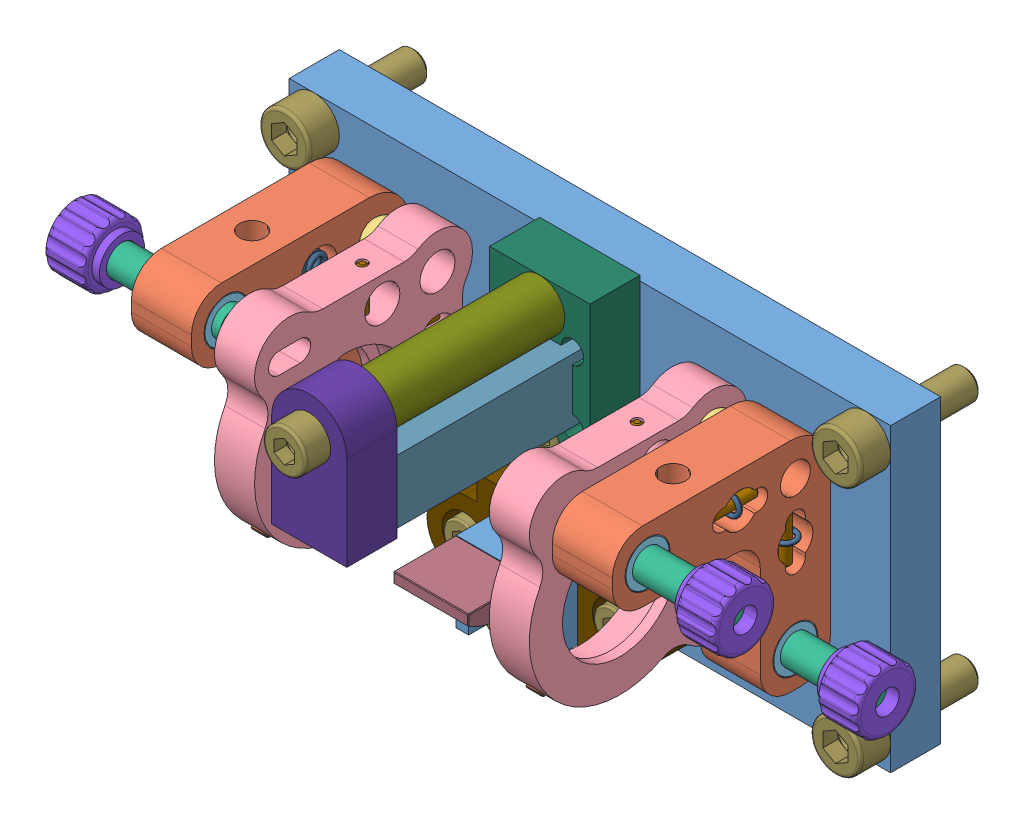
SolidWorks assembly Dye Laser, configuration Standard. Lengths in mm.
Overall size (135.01 63.5 81).
57 component instances, 19 part files, 47 mates.
Components (placement in the parent):
- Base plate-1: Base plate [Standard] at origin size (120 60 10)
- AssemblyEO-1: AssemblyEO [Standard] at (42 -20.7016 6.8571) x (0 -1 0) z (-1 0 0) size (43.98 43.98 44.09)
  - Base-1: Base [Standard] at (-20.7016 28.5429 -6) size (43.5 43.5 12)
  - Ball Bearing 8mm-1: Ball Bearing 8mm [Standard] at (-39.1016 10.1429 8.6458) x (0 0 1) z (-0.991419 0.130726 0) size (8 8 8)
  - Mount-1: Mount [Standard] at (-20.7016 28.5429 10.5822) size (43.5 43.5 8)
  - BushingM6-1: BushingM6 [Standard] at (-39.1016 39.6429 -6) size (9 9 12)
  - BushingM6-2: BushingM6 [Standard] at (-9.6016 10.1429 -6) x (-0.892855 0.450344 0) z (0 0 1) size (9 9 12)
  - Adjustment screw-1: Adjustment screw [Standard] at (-9.6016 10.1429 8.1361) x (0 0 -1) z (0.374671 -0.927158 0) size (30 6 6)
  - Adjustment screw-2: Adjustment screw [Standard] at (-39.1016 39.6429 6.9925) x (0 0 -1) z (-0.963766 0.266748 0) size (30 6 6)
  - BallBearing5mm-1: BallBearing5mm [Standard] at (-9.6016 10.1429 9.2258) x (0.281645 -0.210353 0.936177) z (-0.880072 -0.445363 0.164696) size (5 5 5)
  - BallBearing5mm-2: BallBearing5mm [Standard] at (-39.1016 39.6429 8.0822) x (0.754667 -0.477905 0.449538) z (-0.133948 -0.782951 -0.607491) size (5 5 5)
  - Screw handle-1: Screw handle [Standard] at (-35.834 68.9613 -4.0071) x (0.993846 -0.110766 0) z (0 0 -1) size (13.55 13.55 9.5)
  - Screw handle-2: Screw handle [Standard] at (19.8922 9.5359 -2.8635) x (-0.020573 -0.999788 0) z (0 0 -1) size (13.55 13.55 9.5)
  - 2mm pin-1: 2mm pin [Standard] at (-44.1016 21.1429 14.5822) x (0 0 -1) z (1 0 0) size (2 2 10)
  - 2mm pin-2: 2mm pin [Standard] at (-28.1016 15.1429 14.5822) x (0 0 -1) z (0 -1 0) size (2 2 10)
  - 2mm pin-3: 2mm pin [Standard] at (-33.1016 10.1429 -4) x (0 0 1) z (1 0 0) size (2 2 10)
  - 2mm pin-4: 2mm pin [Standard] at (-39.1016 26.1429 -4) x (0 0 1) z (0 -1 0) size (2 2 10)
  - Gutekunst RZ_081QX_1.stp-1: Gutekunst RZ_081QX_1.stp [Standard] at (-39.1016 21.1429 -2.64) size (4.57 4.57 15.99)
  - Gutekunst RZ_081QX_1.stp-2: Gutekunst RZ_081QX_1.stp [Standard] at (-28.1016 10.1429 -2.64) x (0 -1 0) z (0 0 1) size (4.57 4.57 15.99)
  - socket set screw dog point_din-2: socket set screw dog point_din [DIN 915 - M3 x 5-N] at (-7.6201 41.6243 14.5822) x (-0.707107 -0.707107 0) z (0 0 1) size (5 3 3)
- AssemblyEO-2: AssemblyEO [Standard] at (-42 28.5429 56.1016) x (0 0 1) z (1 0 0) size (43.98 43.98 44.09)
  - Base-1: Base [Standard] at (-20.7016 28.5429 -6) size (43.5 43.5 12)
  - Ball Bearing 8mm-1: Ball Bearing 8mm [Standard] at (-39.1016 10.1429 8.6458) x (0 0 1) z (-0.991419 0.130726 0) size (8 8 8)
  - Mount-1: Mount [Standard] at (-20.7016 28.5429 10.5822) size (43.5 43.5 8)
  - BushingM6-1: BushingM6 [Standard] at (-39.1016 39.6429 -6) size (9 9 12)
  - BushingM6-2: BushingM6 [Standard] at (-9.6016 10.1429 -6) x (-0.892855 0.450344 0) z (0 0 1) size (9 9 12)
  - Adjustment screw-1: Adjustment screw [Standard] at (-9.6016 10.1429 8.1361) x (0 0 -1) z (0.374671 -0.927158 0) size (30 6 6)
  - Adjustment screw-2: Adjustment screw [Standard] at (-39.1016 39.6429 6.9925) x (0 0 -1) z (-0.963766 0.266748 0) size (30 6 6)
  - BallBearing5mm-1: BallBearing5mm [Standard] at (-9.6016 10.1429 9.2258) x (0.281645 -0.210353 0.936177) z (-0.880072 -0.445363 0.164696) size (5 5 5)
  - BallBearing5mm-2: BallBearing5mm [Standard] at (-39.1016 39.6429 8.0822) x (0.754667 -0.477905 0.449538) z (-0.133948 -0.782951 -0.607491) size (5 5 5)
  - Screw handle-1: Screw handle [Standard] at (-35.834 68.9613 -4.0071) x (0.993846 -0.110766 0) z (0 0 -1) size (13.55 13.55 9.5)
  - Screw handle-2: Screw handle [Standard] at (19.8922 9.5359 -2.8635) x (-0.020573 -0.999788 0) z (0 0 -1) size (13.55 13.55 9.5)
  - 2mm pin-1: 2mm pin [Standard] at (-44.1016 21.1429 14.5822) x (0 0 -1) z (1 0 0) size (2 2 10)
  - 2mm pin-2: 2mm pin [Standard] at (-28.1016 15.1429 14.5822) x (0 0 -1) z (0 -1 0) size (2 2 10)
  - 2mm pin-3: 2mm pin [Standard] at (-33.1016 10.1429 -4) x (0 0 1) z (1 0 0) size (2 2 10)
  - 2mm pin-4: 2mm pin [Standard] at (-39.1016 26.1429 -4) x (0 0 1) z (0 -1 0) size (2 2 10)
  - Gutekunst RZ_081QX_1.stp-1: Gutekunst RZ_081QX_1.stp [Standard] at (-39.1016 21.1429 -2.64) size (4.57 4.57 15.99)
  - Gutekunst RZ_081QX_1.stp-2: Gutekunst RZ_081QX_1.stp [Standard] at (-28.1016 10.1429 -2.64) x (0 -1 0) z (0 0 1) size (4.57 4.57 15.99)
  - socket set screw dog point_din-2: socket set screw dog point_din [DIN 915 - M3 x 5-N] at (-7.6201 41.6243 14.5822) x (-0.707107 -0.707107 0) z (0 0 1) size (5 3 3)
- socket head cap screw_din-1: socket head cap screw_din [DIN 912 M4 x 20 --- 20N] at (-42 0 23.6) x (0 0 -1) z (1 0 0) size (24 7 7)
- socket head cap screw_din-2: socket head cap screw_din [DIN 912 M4 x 20 --- 20N] at (42 0 23.6) x (0 0 -1) z (1 0 0) size (24 7 7)
- LJ1638L1-A-Solidworks-1: LJ1638L1-A-Solidworks [Default] at (-0.1002 -15.065 35.4) x (1 0 0) z (0 -1 0) size (15 12.5 3.85)
- Cuvet-1: Cuvet [Standard] at (0.2 14.3 10) size (12.6 12.6 45)
- socket head cap screw_din-3: socket head cap screw_din [DIN 912 M6 x 20 --- 20N] at (-55 -25 16) x (0 0 -1) z (1 0 0) size (26 10 10)
- socket head cap screw_din-4: socket head cap screw_din [DIN 912 M6 x 20 --- 20N] at (55 -25 16) x (0 0 -1) z (1 0 0) size (26 10 10)
- socket head cap screw_din-5: socket head cap screw_din [DIN 912 M6 x 20 --- 20N] at (55 25 16) x (0 0 -1) z (1 0 0) size (26 10 10)
- socket head cap screw_din-6: socket head cap screw_din [DIN 912 M6 x 20 --- 20N] at (-55 25 16) x (0 0 -1) z (1 0 0) size (26 10 10)
- CuvetHolderBase-1: CuvetHolderBase [Standard] at (0 14.5 10) x (0 1 0) z (0 0 1) size (33 20 10)
- socket head cap screw_din-8: socket head cap screw_din [DIN 912 M4 x 16 --- 16N] at (0 3 19.6) x (0 0 -1) z (1 0 0) size (20 7 7)
- CuvetHolderArm-1: CuvetHolderArm [Standard] at (0 26 56) x (0 0 -1) z (-1 0 0) size (44 10 10)
- CuvetHolderClamp-1: CuvetHolderClamp [Standard] at (0 26 56) x (0 1 0) z (0 0 1) size (26.25 15 10)
- socket head cap screw_din-9: socket head cap screw_din [DIN 912 M5 x 16 --- 16N] at (0 26 71) x (0 0 -1) z (1 0 0) size (21 8.5 8.5)
- Rail-1: Rail [Standard] at (22.5 -29.5 10) x (0 1 0) z (0 0 1) size (20 45 10)
- socket head cap screw_din-11: socket head cap screw_din [DIN 912 M4 x 16 --- 16N] at (15 -22 20.9) x (0 0 -1) z (1 0 0) size (20 7 7)
- socket head cap screw_din-12: socket head cap screw_din [DIN 912 M4 x 16 --- 16N] at (-15 -22 20.9) x (0 0 -1) z (1 0 0) size (20 7 7)
- Lensholder-1: Lensholder [Standard] at (7.45 -29.14 19.15) x (0 1 0) z (0 0 1) size (16 15 10)
- socket head cap screw_din-13: socket head cap screw_din [DIN 912 M4 x 10 --- 10N] at (0 -24.5 28.15) x (0 0 -1) z (-0.630869 -0.775889 0) size (14 7 7)
Mates (geometry in assembly coordinates):
- Deckungsgleich1: coincident anti-aligned: plane of Base plate-1 through (0 0 10) normal (0 0 1); plane of AssemblyEO-2/Base-1 through (-36 -18.1 10) normal (0 0 -1)
- Deckungsgleich2: coincident anti-aligned: plane of Base plate-1 through (0 0 10) normal (0 0 1); plane of AssemblyEO-1/Base-1 through (36 17.4 10) normal (0 0 -1)
- Konzentrisch1: concentric aligned: cylinder of Base plate-1 through (-42 0 10) axis (0 0 1) radius 2.1; cylinder of AssemblyEO-2/Base-1 through (-42 0 24) axis (0 0 1) radius 2.5
- Konzentrisch2: concentric aligned: cylinder of Base plate-1 through (42 0 10) axis (0 0 1) radius 2.1; cylinder of AssemblyEO-1/Base-1 through (42 0 24) axis (0 0 1) radius 2.5
- Parallel1: parallel aligned: plane of Base plate-1 through (60 30 10) normal (1 0 0); plane of AssemblyEO-1/Base-1 through (48 6.4 29) normal (1 0 0)
- Parallel2: parallel aligned: plane of Base plate-1 through (-60 30 10) normal (-1 0 0); plane of AssemblyEO-2/Base-1 through (-48 6.4 29) normal (-1 0 0)
- Konzentrisch3: concentric aligned: cylinder of AssemblyEO-2/Base-1 through (-42 0 24) axis (0 0 1) radius 2.5; cylinder of socket head cap screw_din-1 through (-42 0 55.35) axis (0 0 1) radius 3.5
- Deckungsgleich3: coincident anti-aligned: plane of AssemblyEO-2/Base-1 through (-42 -2.5 19.6) normal (0 0 1); plane of socket head cap screw_din-1 through (-42 3.5 19.6) normal (0 0 -1)
- Konzentrisch4: concentric aligned: cylinder of AssemblyEO-1/Base-1 through (42 0 24) axis (0 0 1) radius 2.5; cylinder of socket head cap screw_din-2 through (42 0 55.35) axis (0 0 1) radius 3.5
- Deckungsgleich4: coincident anti-aligned: plane of AssemblyEO-1/Base-1 through (42 -2.5 19.6) normal (0 0 1); plane of socket head cap screw_din-2 through (42 3.5 19.6) normal (0 0 -1)
- Deckungsgleich5: coincident anti-aligned: plane of Base plate-1 through (0 0 10) normal (0 0 1); plane of Cuvet-1 through (0.2 14.3 10) normal (0 0 -1)
- Konzentrisch5: concentric aligned: cylinder of Base plate-1 through (-55 -25 10) axis (0 0 1) radius 2.5; cylinder of socket head cap screw_din-3 through (-55 -25 47.75) axis (0 0 1) radius 5
- Deckungsgleich6: coincident anti-aligned: plane of Base plate-1 through (0 0 10) normal (0 0 1); plane of socket head cap screw_din-3 through (-55 -20 10) normal (0 0 -1)
- Konzentrisch6: concentric aligned: cylinder of Base plate-1 through (55 -25 10) axis (0 0 1) radius 2.5; cylinder of socket head cap screw_din-4 through (55 -25 47.75) axis (0 0 1) radius 5
- Deckungsgleich7: coincident anti-aligned: plane of Base plate-1 through (0 0 10) normal (0 0 1); plane of socket head cap screw_din-4 through (55 -20 10) normal (0 0 -1)
- Konzentrisch7: concentric aligned: cylinder of Base plate-1 through (55 25 10) axis (0 0 1) radius 2.5; cylinder of socket head cap screw_din-5 through (55 25 47.75) axis (0 0 1) radius 5
- Deckungsgleich8: coincident anti-aligned: plane of Base plate-1 through (0 0 10) normal (0 0 1); plane of socket head cap screw_din-5 through (55 30 10) normal (0 0 -1)
- Konzentrisch8: concentric aligned: cylinder of Base plate-1 through (-55 25 10) axis (0 0 1) radius 2.5; cylinder of socket head cap screw_din-6 through (-55 25 47.75) axis (0 0 1) radius 5
- Deckungsgleich9: coincident anti-aligned: plane of Base plate-1 through (0 0 10) normal (0 0 1); plane of socket head cap screw_din-6 through (-55 30 10) normal (0 0 -1)
- Konzentrisch9: concentric aligned: cylinder of Base plate-1 through (0 3 10) axis (0 0 1) radius 1.65; cylinder of CuvetHolderBase-1 through (0 3 20) axis (0 0 1) radius 2.25
- Konzentrisch11: concentric aligned: cylinder of CuvetHolderBase-1 through (0 3 20) axis (0 0 1) radius 2.25; cylinder of socket head cap screw_din-8 through (0 3 51.35) axis (0 0 1) radius 3.5
- Deckungsgleich11: coincident anti-aligned: plane of CuvetHolderBase-1 through (0 5.25 15.6) normal (0 0 1); plane of socket head cap screw_din-8 through (0 6.5 15.6) normal (0 0 -1)
- Deckungsgleich12: coincident anti-aligned: plane of Base plate-1 through (0 0 10) normal (0 0 1); plane of CuvetHolderBase-1 through (0 14.5 10) normal (0 0 -1)
- Deckungsgleich13: coincident anti-aligned: plane of Cuvet-1 through (6.5 8 55) normal (0 -1 0); plane of CuvetHolderBase-1 through (-6.5 8 20) normal (0 1 0)
- Deckungsgleich14: coincident anti-aligned: plane of Cuvet-1 through (6.5 8 55) normal (1 0 0); plane of CuvetHolderBase-1 through (6.5 8 20) normal (-1 0 0)
- Parallel3: parallel aligned: plane of Base plate-1 through (-60 30 10) normal (0 1 0); plane of CuvetHolderBase-1 through (10 31 20) normal (0 1 0)
- Konzentrisch12: concentric aligned: cylinder of CuvetHolderBase-1 through (0 26 20) axis (0 0 1) radius 2.1; cylinder of CuvetHolderArm-1 through (0 26 56) axis (0 0 1) radius 2.5
- Deckungsgleich15: coincident anti-aligned: plane of CuvetHolderBase-1 through (0 14.5 20) normal (0 0 1); plane of CuvetHolderArm-1 through (0 21 20) normal (0 0 -1)
- Konzentrisch13: concentric anti-aligned: cylinder of CuvetHolderArm-1 through (0 26 56) axis (0 0 1) radius 2.1; cylinder of CuvetHolderClamp-1 through (0 26 66) axis (0 0 -1) radius 2.75
- Deckungsgleich16: coincident anti-aligned: plane of CuvetHolderArm-1 through (0 26 56) normal (0 0 1); plane of CuvetHolderClamp-1 through (0 26 56) normal (0 0 -1)
- Parallel4: parallel aligned: plane of CuvetHolderBase-1 through (10 -2 20) normal (1 0 0); plane of CuvetHolderClamp-1 through (7.5 26 66) normal (1 0 0)
- Konzentrisch14: concentric anti-aligned: cylinder of CuvetHolderClamp-1 through (0 26 66) axis (0 0 -1) radius 2.75; cylinder of socket head cap screw_din-9 through (0 26 102.75) axis (0 0 1) radius 4.25
- Deckungsgleich17: coincident anti-aligned: plane of CuvetHolderClamp-1 through (0 26 66) normal (0 0 1); plane of socket head cap screw_din-9 through (0 30.25 66) normal (0 0 -1)
- Abstand1: distance = 22.19 mm aligned: plane of LJ1638L1-A-Solidworks-1 through (7.3998 -13.14 41.65) normal (0 1 0); plane of Cuvet-1 through (5.45 9.05 -4.8492) normal (0 1 0)
- Deckungsgleich18: coincident anti-aligned: plane of Base plate-1 through (0 0 10) normal (0 0 1); plane of Rail-1 through (22.5 -29.5 10) normal (0 0 -1)
- Konzentrisch15: concentric aligned: cylinder of Base plate-1 through (-15 -22 10) axis (0 0 1) radius 1.65; cylinder of Rail-1 through (-15 -22 20) axis (0 0 1) radius 2.25
- Konzentrisch16: concentric aligned: cylinder of Base plate-1 through (15 -22 10) axis (0 0 1) radius 1.65; cylinder of Rail-1 through (15 -22 20) axis (0 0 1) radius 2.25
- Konzentrisch17: concentric aligned: cylinder of Rail-1 through (15 -22 20) axis (0 0 1) radius 2.25; cylinder of socket head cap screw_din-11 through (15 -22 52.65) axis (0 0 1) radius 3.5
- Deckungsgleich19: coincident anti-aligned: plane of Rail-1 through (15 -19.75 16.9) normal (0 0 1); plane of socket head cap screw_din-11 through (15 -18.5 16.9) normal (0 0 -1)
- Konzentrisch18: concentric aligned: cylinder of Rail-1 through (-15 -22 20) axis (0 0 1) radius 2.25; cylinder of socket head cap screw_din-12 through (-15 -22 52.65) axis (0 0 1) radius 3.5
- Deckungsgleich20: coincident anti-aligned: plane of Rail-1 through (-15 -19.75 16.9) normal (0 0 1); plane of socket head cap screw_din-12 through (-15 -18.5 16.9) normal (0 0 -1)
- Abstand2: distance = 10 mm anti-aligned: plane of LJ1638L1-A-Solidworks-1 through (7.3998 -13.14 29.15) normal (0 0 -1); plane of Rail-1 through (22.5 -29.5 19.15) normal (0 0 1)
- Deckungsgleich21: coincident anti-aligned: plane of Rail-1 through (22.5 -29.5 19.15) normal (0 0 1); plane of Lensholder-1 through (7.45 -29.14 19.15) normal (0 0 -1)
- Deckungsgleich22: coincident: line of Rail-1 through (-7.55 -9.5 20) axis (0 -1 0); plane of Lensholder-1 through (-7.55 -29.14 29.15) normal (-1 0 0)
- Deckungsgleich23: coincident aligned: plane of LJ1638L1-A-Solidworks-1 through (7.3998 -13.14 41.65) normal (0 1 0); plane of Lensholder-1 through (7.45 -13.14 29.15) normal (0 1 0)
- Konzentrisch19: concentric aligned: cylinder of Rail-1 through (0 -24.5 19.15) axis (0 0 1) radius 1.65; cylinder of socket head cap screw_din-13 through (0 -24.5 59.9) axis (0 0 1) radius 2
- Deckungsgleich24: coincident anti-aligned: plane of Lensholder-1 through (-0.05 -29.14 24.15) normal (0 0 1); plane of socket head cap screw_din-13 through (2.7156 -26.708 24.15) normal (0 0 -1)
